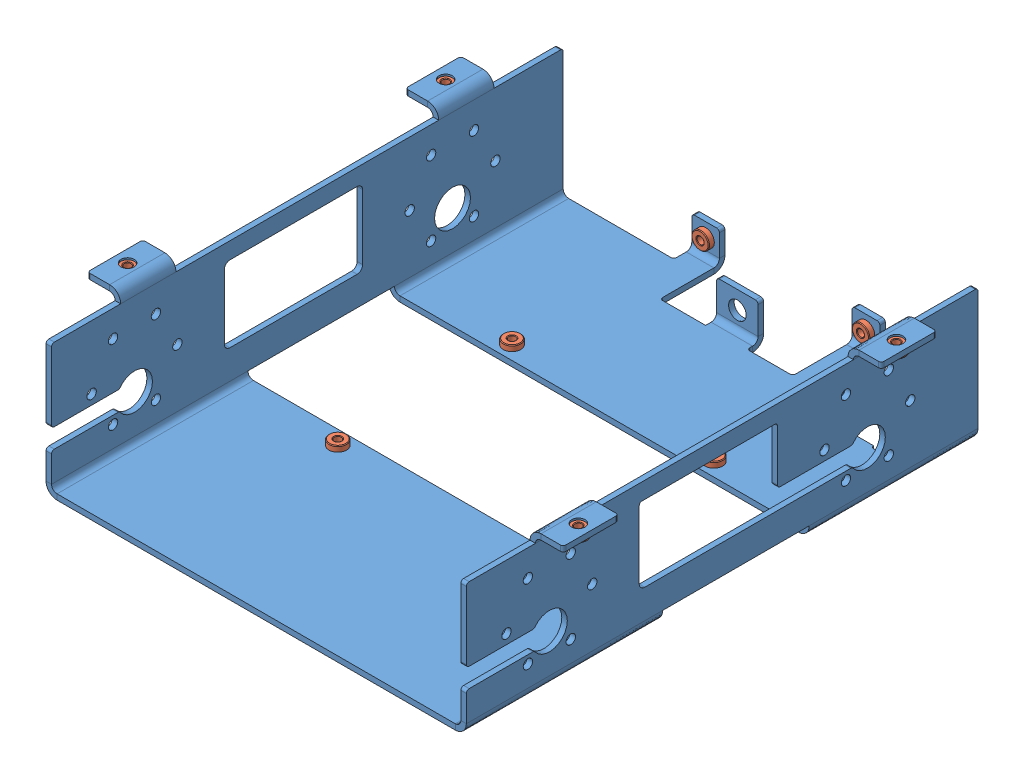
SolidWorks assembly HEL-03-01009-00, configuration Standard. Lengths in mm.
Overall size (172 52 193.5).
11 component instances, 2 part files, 20 mates.
Components (placement in the parent):
- HEL-04-01000-02-1: HEL-04-01000-02 [Standard] at origin size (172 52 193.5)
- aluminum nut_pmm-11: aluminum nut_pmm [PEM CLA-M3-2 ---N] at (81.5 48 -150) x (0.837169 0 0.546944) z (0.546944 0 -0.837169) size (6.3 3.37 6.3)
- aluminum nut_pmm-12: aluminum nut_pmm [PEM CLA-M3-2 ---N] at (81.5 48 -35) x (0.837169 0 0.546944) z (0.546944 0 -0.837169) size (6.3 3.37 6.3)
- aluminum nut_pmm-13: aluminum nut_pmm [PEM CLA-M3-2 ---N] at (-81.5 48 -150) x (0.837169 0 0.546944) z (0.546944 0 -0.837169) size (6.3 3.37 6.3)
- aluminum nut_pmm-14: aluminum nut_pmm [PEM CLA-M3-2 ---N] at (-81.5 48 -35) x (0.837169 0 0.546944) z (0.546944 0 -0.837169) size (6.3 3.37 6.3)
- aluminum nut_pmm-15: aluminum nut_pmm [PEM CLA-M3-2 ---N] at (29 6 -191.5) x (1 0 0) z (0 -1 0) size (6.3 3.37 6.3)
- aluminum nut_pmm-16: aluminum nut_pmm [PEM CLA-M3-2 ---N] at (-29 6 -191.5) x (1 0 0) z (0 -1 0) size (6.3 3.37 6.3)
- aluminum nut_pmm-17: aluminum nut_pmm [PEM CLA-M3-2 ---N] at (-36.5 0 -129) size (6.3 3.37 6.3)
- aluminum nut_pmm-18: aluminum nut_pmm [PEM CLA-M3-2 ---N] at (-36.5 0 -66) size (6.3 3.37 6.3)
- aluminum nut_pmm-19: aluminum nut_pmm [PEM CLA-M3-2 ---N] at (36.5 0 -66) size (6.3 3.37 6.3)
- aluminum nut_pmm-20: aluminum nut_pmm [PEM CLA-M3-2 ---N] at (36.5 0 -129) x (-0.993512 0 -0.113726) z (0.113726 0 -0.993512) size (6.3 3.37 6.3)
Mates (geometry in assembly coordinates):
- Konzentrisch12: concentric aligned: cylinder of HEL-04-01000-02-1 through (81.5 50 -150) axis (0 1 0) radius 2.395; cylinder of aluminum nut_pmm-11 through (81.5 48 -150) axis (0 1 0) radius 3.15
- Deckungsgleich12: coincident anti-aligned: plane of HEL-04-01000-02-1 through (0 48 -185) normal (0 -1 0); plane of aluminum nut_pmm-11 through (83.215 48 -148.8795) normal (0 1 0)
- Konzentrisch13: concentric aligned: cylinder of HEL-04-01000-02-1 through (81.5 50 -35) axis (0 1 0) radius 2.395; cylinder of aluminum nut_pmm-12 through (81.5 48 -35) axis (0 1 0) radius 3.15
- Deckungsgleich13: coincident anti-aligned: plane of HEL-04-01000-02-1 through (0 48 -185) normal (0 -1 0); plane of aluminum nut_pmm-12 through (83.215 48 -33.8795) normal (0 1 0)
- Konzentrisch14: concentric aligned: cylinder of HEL-04-01000-02-1 through (-81.5 50 -150) axis (0 1 0) radius 2.395; cylinder of aluminum nut_pmm-13 through (-81.5 48 -150) axis (0 1 0) radius 3.15
- Deckungsgleich14: coincident anti-aligned: plane of HEL-04-01000-02-1 through (0 48 -185) normal (0 -1 0); plane of aluminum nut_pmm-13 through (-79.785 48 -148.8795) normal (0 1 0)
- Konzentrisch15: concentric aligned: cylinder of HEL-04-01000-02-1 through (-81.5 50 -35) axis (0 1 0) radius 2.395; cylinder of aluminum nut_pmm-14 through (-81.5 48 -35) axis (0 1 0) radius 3.15
- Deckungsgleich15: coincident anti-aligned: plane of HEL-04-01000-02-1 through (0 48 -185) normal (0 -1 0); plane of aluminum nut_pmm-14 through (-79.785 48 -33.8795) normal (0 1 0)
- Konzentrisch16: concentric anti-aligned: cylinder of HEL-04-01000-02-1 through (29 6 -193.5) axis (0 0 1) radius 2.395; cylinder of aluminum nut_pmm-15 through (29 6 -191.5) axis (0 0 -1) radius 3.15
- Deckungsgleich16: coincident anti-aligned: plane of HEL-04-01000-02-1 through (0 0 -191.5) normal (0 0 1); plane of aluminum nut_pmm-15 through (31.0486 6 -191.5) normal (0 0 -1)
- Konzentrisch17: concentric anti-aligned: cylinder of HEL-04-01000-02-1 through (-29 6 -193.5) axis (0 0 1) radius 2.395; cylinder of aluminum nut_pmm-16 through (-29 6 -191.5) axis (0 0 -1) radius 3.15
- Deckungsgleich17: coincident anti-aligned: plane of HEL-04-01000-02-1 through (0 0 -191.5) normal (0 0 1); plane of aluminum nut_pmm-16 through (-26.9514 6 -191.5) normal (0 0 -1)
- Konzentrisch18: concentric anti-aligned: cylinder of HEL-04-01000-02-1 through (-36.5 0 -129) axis (0 1 0) radius 2.395; cylinder of aluminum nut_pmm-17 through (-36.5 0 -129) axis (0 -1 0) radius 3.15
- Deckungsgleich18: coincident anti-aligned: plane of HEL-04-01000-02-1 through (-74 0 -185) normal (0 1 0); plane of aluminum nut_pmm-17 through (-34.4514 0 -129) normal (0 -1 0)
- Konzentrisch19: concentric anti-aligned: cylinder of HEL-04-01000-02-1 through (-36.5 0 -66) axis (0 1 0) radius 2.395; cylinder of aluminum nut_pmm-18 through (-36.5 0 -66) axis (0 -1 0) radius 3.15
- Deckungsgleich19: coincident anti-aligned: plane of HEL-04-01000-02-1 through (-74 0 -185) normal (0 1 0); plane of aluminum nut_pmm-18 through (-34.4514 0 -66) normal (0 -1 0)
- Konzentrisch20: concentric anti-aligned: cylinder of HEL-04-01000-02-1 through (36.5 0 -66) axis (0 1 0) radius 2.395; cylinder of aluminum nut_pmm-19 through (36.5 0 -66) axis (0 -1 0) radius 3.15
- Deckungsgleich20: coincident anti-aligned: plane of HEL-04-01000-02-1 through (-74 0 -185) normal (0 1 0); plane of aluminum nut_pmm-19 through (38.5486 0 -66) normal (0 -1 0)
- Konzentrisch21: concentric anti-aligned: cylinder of HEL-04-01000-02-1 through (36.5 0 -129) axis (0 1 0) radius 2.395; cylinder of aluminum nut_pmm-20 through (36.5 0 -129) axis (0 -1 0) radius 3.15
- Deckungsgleich21: coincident anti-aligned: plane of HEL-04-01000-02-1 through (-74 0 -185) normal (0 1 0); plane of aluminum nut_pmm-20 through (34.4647 0 -129.233) normal (0 -1 0)
